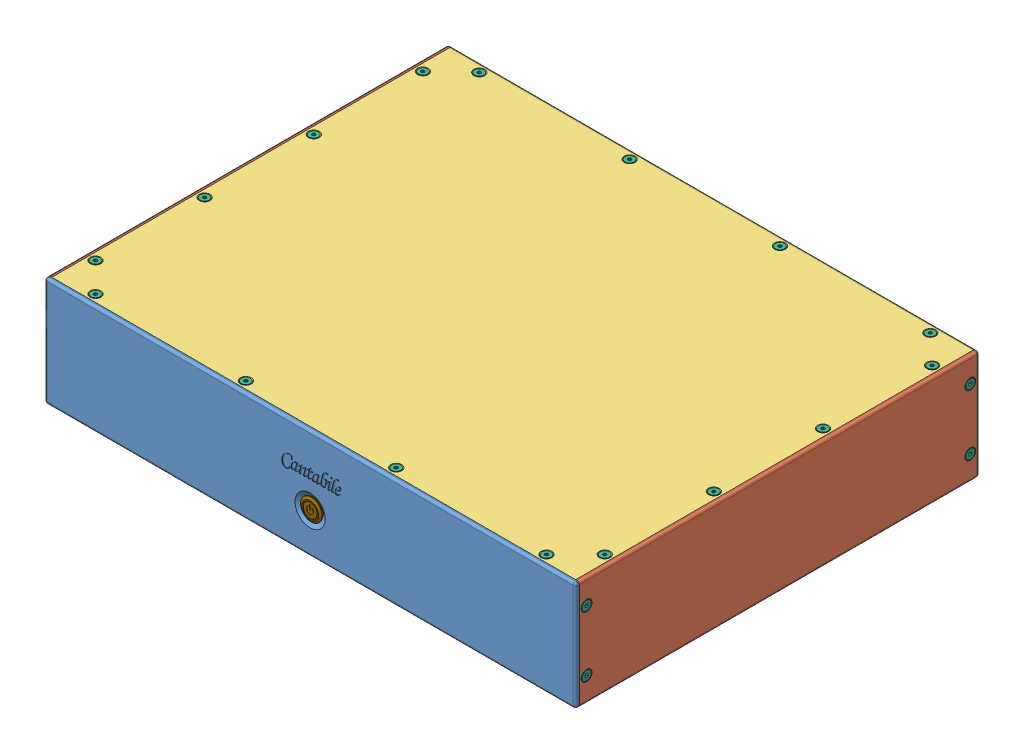
SolidWorks assembly 組合, configuration 預設. Lengths in mm.
Overall size (438 90 338.01).
55 component instances, 9 part files, 72 mates.
Components (placement in the parent):
- FrontPanel-1: FrontPanel [預設] at (-0.5858 -0.5858 -10.5) size (438 90 12.5)
- SidePanel-1: SidePanel [預設] at (437.4142 89.4142 -1) x (0 0 -1) z (-1 0 0) size (330 90 12.5)
- SidePanel-2: SidePanel [預設] at (-0.5858 -0.5858 -1) x (0 0 -1) z (1 0 0) size (330 90 12.5)
- TOP-1: TOP [預設] at (434.4142 85.4142 -331) x (-1 0 0) z (0 0 -1) size (432 4 330)
- Bottom-1: Bottom [預設] at (2.4142 3.4142 -331) x (1 0 0) z (0 0 -1) size (432 4 330)
- BackPanel-1: BackPanel [預設] at (424.9142 3.4142 -318.5) x (-1 0 0) z (0 0 -1) size (413 82 12.5)
- socket countersunk head screw_iso-1: socket countersunk head screw_iso [ISO 10642 - M4 x 8 --- 8N] at (404.4142 89.4142 -7) x (0 -1 0) z (0 0 1) size (8 7.53 7.53)
- socket countersunk head screw_iso-2: socket countersunk head screw_iso [ISO 10642 - M4 x 8 --- 8N] at (437.4142 69.4142 -323.5) x (-1 0 0) z (0 0.924225 0.381849) size (8 7.53 7.53)
- socket countersunk head screw_iso-3: socket countersunk head screw_iso [ISO 10642 - M4 x 8 --- 8N] at (280.4142 89.4142 -323.5) x (0 -1 0) z (0 0 1) size (8 7.53 7.53)
- socket countersunk head screw_iso-4: socket countersunk head screw_iso [ISO 10642 - M4 x 8 --- 8N] at (428.4142 89.4142 -211) x (0 -1 0) z (0 0 1) size (8 7.53 7.53)
- socket countersunk head screw_iso-5: socket countersunk head screw_iso [ISO 10642 - M4 x 8 --- 8N] at (404.4142 89.4142 -323.5) x (0 -1 0) z (0 0 1) size (8 7.53 7.53)
- socket countersunk head screw_iso-6: socket countersunk head screw_iso [ISO 10642 - M4 x 8 --- 8N] at (437.4142 19.4142 -323.5) x (-1 0 0) z (0 0.924225 0.381849) size (8 7.53 7.53)
- socket countersunk head screw_iso-7: socket countersunk head screw_iso [ISO 10642 - M4 x 8 --- 8N] at (428.4142 89.4142 -301) x (0 -1 0) z (0 0 1) size (8 7.53 7.53)
- socket countersunk head screw_iso-8: socket countersunk head screw_iso [ISO 10642 - M4 x 8 --- 8N] at (428.4142 89.4142 -121) x (0 -1 0) z (0 0 1) size (8 7.53 7.53)
- socket countersunk head screw_iso-9: socket countersunk head screw_iso [ISO 10642 - M4 x 8 --- 8N] at (428.4142 89.4142 -31) x (0 -1 0) z (0 0 1) size (8 7.53 7.53)
- socket countersunk head screw_iso-10: socket countersunk head screw_iso [ISO 10642 - M4 x 8 --- 8N] at (8.4142 -0.5858 -31) x (0 1 0) z (0 0 1) size (8 7.53 7.53)
- socket countersunk head screw_iso-11: socket countersunk head screw_iso [ISO 10642 - M4 x 8 --- 8N] at (156.4142 89.4142 -7) x (0 -1 0) z (0 0 1) size (8 7.53 7.53)
- socket countersunk head screw_iso-12: socket countersunk head screw_iso [ISO 10642 - M4 x 8 --- 8N] at (8.4142 89.4142 -31) x (0 -1 0) z (0 0 1) size (8 7.53 7.53)
- socket countersunk head screw_iso-13: socket countersunk head screw_iso [ISO 10642 - M4 x 8 --- 8N] at (428.4142 -0.5858 -121) x (0 1 0) z (0 0 1) size (8 7.53 7.53)
- socket countersunk head screw_iso-14: socket countersunk head screw_iso [ISO 10642 - M4 x 8 --- 8N] at (32.4142 89.4142 -7) x (0 -1 0) z (0 0 1) size (8 7.53 7.53)
- socket countersunk head screw_iso-15: socket countersunk head screw_iso [ISO 10642 - M4 x 8 --- 8N] at (437.4142 69.4142 -7) x (-1 0 0) z (0 0.924225 0.381849) size (8 7.53 7.53)
- socket countersunk head screw_iso-16: socket countersunk head screw_iso [ISO 10642 - M4 x 8 --- 8N] at (437.4142 19.4142 -7) x (-1 0 0) z (0 0.924225 0.381849) size (8 7.53 7.53)
- socket countersunk head screw_iso-17: socket countersunk head screw_iso [ISO 10642 - M4 x 8 --- 8N] at (428.4142 -0.5858 -301) x (0 1 0) z (0 0 1) size (8 7.53 7.53)
- socket countersunk head screw_iso-18: socket countersunk head screw_iso [ISO 10642 - M4 x 8 --- 8N] at (280.4142 89.4142 -7) x (0 -1 0) z (0 0 1) size (8 7.53 7.53)
- socket countersunk head screw_iso-19: socket countersunk head screw_iso [ISO 10642 - M4 x 8 --- 8N] at (8.4142 89.4142 -121) x (0 -1 0) z (0 0 1) size (8 7.53 7.53)
- socket countersunk head screw_iso-20: socket countersunk head screw_iso [ISO 10642 - M4 x 8 --- 8N] at (280.4142 -0.5858 -323.5) x (0 1 0) z (0 0 1) size (8 7.53 7.53)
- socket countersunk head screw_iso-21: socket countersunk head screw_iso [ISO 10642 - M4 x 8 --- 8N] at (156.4142 -0.5858 -323.5) x (0 1 0) z (0 0 1) size (8 7.53 7.53)
- socket countersunk head screw_iso-22: socket countersunk head screw_iso [ISO 10642 - M4 x 8 --- 8N] at (428.4142 -0.5858 -211) x (0 1 0) z (0 0 1) size (8 7.53 7.53)
- socket countersunk head screw_iso-23: socket countersunk head screw_iso [ISO 10642 - M4 x 8 --- 8N] at (428.4142 -0.5858 -31) x (0 1 0) z (0 0 1) size (8 7.53 7.53)
- socket countersunk head screw_iso-24: socket countersunk head screw_iso [ISO 10642 - M4 x 8 --- 8N] at (32.4142 -0.5858 -323.5) x (0 1 0) z (0 0 1) size (8 7.53 7.53)
- socket countersunk head screw_iso-25: socket countersunk head screw_iso [ISO 10642 - M4 x 8 --- 8N] at (156.4142 89.4142 -323.5) x (0 -1 0) z (0 0 1) size (8 7.53 7.53)
- socket countersunk head screw_iso-26: socket countersunk head screw_iso [ISO 10642 - M4 x 8 --- 8N] at (404.4142 -0.5858 -7) x (0 1 0) z (0 0 1) size (8 7.53 7.53)
- socket countersunk head screw_iso-27: socket countersunk head screw_iso [ISO 10642 - M4 x 8 --- 8N] at (8.4142 89.4142 -301) x (0 -1 0) z (0 0 1) size (8 7.53 7.53)
- socket countersunk head screw_iso-28: socket countersunk head screw_iso [ISO 10642 - M4 x 8 --- 8N] at (280.4142 -0.5858 -7) x (0 1 0) z (0 0 1) size (8 7.53 7.53)
- socket countersunk head screw_iso-29: socket countersunk head screw_iso [ISO 10642 - M4 x 8 --- 8N] at (32.4142 89.4142 -323.5) x (0 -1 0) z (0 0 1) size (8 7.53 7.53)
- socket countersunk head screw_iso-30: socket countersunk head screw_iso [ISO 10642 - M4 x 8 --- 8N] at (8.4142 -0.5858 -211) x (0 1 0) z (0 0 1) size (8 7.53 7.53)
- socket countersunk head screw_iso-31: socket countersunk head screw_iso [ISO 10642 - M4 x 8 --- 8N] at (8.4142 89.4142 -211) x (0 -1 0) z (0 0 1) size (8 7.53 7.53)
- socket countersunk head screw_iso-32: socket countersunk head screw_iso [ISO 10642 - M4 x 8 --- 8N] at (156.4142 -0.5858 -7) x (0 1 0) z (0 0 1) size (8 7.53 7.53)
- socket countersunk head screw_iso-33: socket countersunk head screw_iso [ISO 10642 - M4 x 8 --- 8N] at (32.4142 -0.5858 -7) x (0 1 0) z (0 0 1) size (8 7.53 7.53)
- socket countersunk head screw_iso-34: socket countersunk head screw_iso [ISO 10642 - M4 x 8 --- 8N] at (8.4142 -0.5858 -301) x (0 1 0) z (0 0 1) size (8 7.53 7.53)
- socket countersunk head screw_iso-35: socket countersunk head screw_iso [ISO 10642 - M4 x 8 --- 8N] at (8.4142 -0.5858 -121) x (0 1 0) z (0 0 1) size (8 7.53 7.53)
- socket countersunk head screw_iso-36: socket countersunk head screw_iso [ISO 10642 - M4 x 8 --- 8N] at (-0.5858 19.4142 -323.5) size (8 7.53 7.53)
- socket countersunk head screw_iso-37: socket countersunk head screw_iso [ISO 10642 - M4 x 8 --- 8N] at (-0.5858 19.4142 -7) size (8 7.53 7.53)
- socket countersunk head screw_iso-38: socket countersunk head screw_iso [ISO 10642 - M4 x 8 --- 8N] at (-0.5858 69.4142 -7) x (1 0 0) z (0 0 -1) size (8 7.53 7.53)
- socket countersunk head screw_iso-39: socket countersunk head screw_iso [ISO 10642 - M4 x 8 --- 8N] at (-0.5858 69.4142 -323.5) size (8 7.53 7.53)
- RCA-1: RCA [預設] at (61.9142 44.4142 -329) x (1 0 0) z (0 0 -1) size (26 31 28.3)
- RCA-2: RCA [預設] at (374.9142 44.4142 -329) x (1 0 0) z (0 0 -1) size (26 31 28.3)
- socket countersunk head screw_iso-40: socket countersunk head screw_iso [ISO 10642 - M3 x 8 --- 8N] at (365.4142 32.4142 -331.36) x (0 0 1) z (-1 0 0) size (8 5.54 5.54)
- socket countersunk head screw_iso-41: socket countersunk head screw_iso [ISO 10642 - M3 x 8 --- 8N] at (384.4142 56.4142 -331.36) x (0 0 1) z (-1 0 0) size (8 5.54 5.54)
- socket countersunk head screw_iso-42: socket countersunk head screw_iso [ISO 10642 - M3 x 8 --- 8N] at (71.4142 56.4142 -331.36) x (0 0 1) z (-1 0 0) size (8 5.54 5.54)
- socket countersunk head screw_iso-43: socket countersunk head screw_iso [ISO 10642 - M3 x 8 --- 8N] at (200.4142 28.6642 -333.0929) x (0 0 1) z (-1 0 0) size (8 5.54 5.54)
- socket countersunk head screw_iso-44: socket countersunk head screw_iso [ISO 10642 - M3 x 8 --- 8N] at (52.4142 32.4142 -331.36) x (0 0 1) z (-1 0 0) size (8 5.54 5.54)
- socket countersunk head screw_iso-45: socket countersunk head screw_iso [ISO 10642 - M3 x 8 --- 8N] at (236.4142 28.6642 -333.0929) x (0 0 1) z (-1 0 0) size (8 5.54 5.54)
- IEC-320-1: IEC-320 [預設] at (218.4142 22.9642 -333.5) x (-1 0 0) z (0 0 -1) size (44.12 34 28.26)
- LED SWITCH-1: LED SWITCH [預設] at (218.4142 32.4142 0.5) size (17.8 17.8 37.5)
Mates (geometry in assembly coordinates):
- 重合/共線/共點3: coincident anti-aligned: plane of FrontPanel-1 through (437.4142 -0.5858 -1) normal (0 0 -1); plane of SidePanel-2 through (11.9142 -0.5858 -1) normal (0 0 1)
- 重合/共線/共點4: coincident anti-aligned: line of FrontPanel-1 through (11.9142 85.4142 -1) axis (0 0 -1); line of SidePanel-2 through (11.9142 85.4142 -331) axis (0 0 1)
- 重合/共線/共點8: coordinate: moEndPointRef_w of FrontPanel-1; point of assembly
- 重合/共線/共點16: coincident anti-aligned: plane of FrontPanel-1 through (437.4142 -0.5858 -1) normal (0 0 -1); plane of SidePanel-1 through (424.9142 89.4142 -1) normal (0 0 1)
- 重合/共線/共點17: coincident anti-aligned: line of FrontPanel-1 through (424.9142 3.4142 -1) axis (0 0 -1); line of SidePanel-1 through (424.9142 3.4142 -331) axis (0 0 1)
- 重合/共線/共點53: coincident anti-aligned: plane of FrontPanel-1 through (11.9142 -0.5858 -10.5) normal (-1 0 0); plane of SidePanel-2 through (11.9142 -0.5858 -1) normal (1 0 0)
- 重合/共線/共點56: coincident anti-aligned: plane of SidePanel-2 through (11.9142 85.4142 -331) normal (0 1 0); plane of TOP-1 through (434.4142 85.4142 -331) normal (0 -1 0)
- 重合/共線/共點57: coincident aligned: line of FrontPanel-1 through (11.9142 85.4142 -1) axis (1 0 0); line of TOP-1 through (2.4142 85.4142 -1) axis (1 0 0)
- 重合/共線/共點58: coincident anti-aligned: line of SidePanel-1 through (434.4142 89.4142 -329) axis (0 0 1); line of TOP-1 through (434.4142 89.4142 -1) axis (0 0 -1)
- 重合/共線/共點75: coincident anti-aligned: plane of SidePanel-1 through (434.4142 -0.5858 -331) normal (-1 0 0); plane of Bottom-1 through (434.4142 -0.5858 -331) normal (1 0 0)
- 重合/共線/共點76: coincident anti-aligned: line of SidePanel-1 through (434.4142 3.4142 -331) axis (-1 0 0); line of Bottom-1 through (2.4142 3.4142 -331) axis (1 0 0)
- 重合/共線/共點77: coincident anti-aligned: plane of SidePanel-2 through (11.9142 3.4142 -331) normal (0 -1 0); plane of Bottom-1 through (2.4142 3.4142 -331) normal (0 1 0)
- 重合/共線/共點78: coincident aligned: cone of SidePanel-1 through (437.4142 69.4142 -323.5) axis (-1 0 0); cone of socket countersunk head screw_iso-2 through (436.6992 69.4142 -323.5) axis (-1 0 0)
- 重合/共線/共點79: coincident aligned: cone of SidePanel-1 through (437.4142 19.4142 -323.5) axis (-1 0 0); cone of socket countersunk head screw_iso-6 through (436.6992 19.4142 -323.5) axis (-1 0 0)
- 重合/共線/共點80: coincident aligned: cone of TOP-1 through (404.4142 89.4142 -323.5) axis (0 -1 0); cone of socket countersunk head screw_iso-5 through (404.4142 88.6992 -323.5) axis (0 -1 0)
- 重合/共線/共點81: coincident aligned: cone of TOP-1 through (280.4142 89.4142 -323.5) axis (0 -1 0); cone of socket countersunk head screw_iso-3 through (280.4142 88.6992 -323.5) axis (0 -1 0)
- 重合/共線/共點82: coincident aligned: cone of TOP-1 through (428.4142 89.4142 -211) axis (0 -1 0); cone of socket countersunk head screw_iso-4 through (428.4142 88.6992 -211) axis (0 -1 0)
- 重合/共線/共點83: coincident aligned: cone of TOP-1 through (428.4142 89.4142 -301) axis (0 -1 0); cone of socket countersunk head screw_iso-7 through (428.4142 88.6992 -301) axis (0 -1 0)
- 重合/共線/共點84: coincident aligned: cone of TOP-1 through (428.4142 89.4142 -121) axis (0 -1 0); cone of socket countersunk head screw_iso-8 through (428.4142 88.6992 -121) axis (0 -1 0)
- 重合/共線/共點85: coincident aligned: cone of TOP-1 through (156.4142 89.4142 -323.5) axis (0 -1 0); cone of socket countersunk head screw_iso-25 through (156.4142 88.6992 -323.5) axis (0 -1 0)
- 重合/共線/共點86: coincident aligned: cone of TOP-1 through (428.4142 89.4142 -31) axis (0 -1 0); cone of socket countersunk head screw_iso-9 through (428.4142 88.6992 -31) axis (0 -1 0)
- 重合/共線/共點87: coincident aligned: cone of TOP-1 through (404.4142 89.4142 -7) axis (0 -1 0); cone of socket countersunk head screw_iso-1 through (404.4142 88.6992 -7) axis (0 -1 0)
- 重合/共線/共點88: coincident aligned: cone of SidePanel-1 through (437.4142 69.4142 -7) axis (-1 0 0); cone of socket countersunk head screw_iso-15 through (436.6992 69.4142 -7) axis (-1 0 0)
- 重合/共線/共點89: coincident aligned: cone of SidePanel-1 through (437.4142 19.4142 -7) axis (-1 0 0); cone of socket countersunk head screw_iso-16 through (436.6992 19.4142 -7) axis (-1 0 0)
- 重合/共線/共點90: coincident aligned: cone of TOP-1 through (280.4142 89.4142 -7) axis (0 -1 0); cone of socket countersunk head screw_iso-18 through (280.4142 88.6992 -7) axis (0 -1 0)
- 重合/共線/共點91: coincident aligned: cone of TOP-1 through (32.4142 89.4142 -323.5) axis (0 -1 0); cone of socket countersunk head screw_iso-29 through (32.4142 88.6992 -323.5) axis (0 -1 0)
- 重合/共線/共點92: coincident aligned: cone of TOP-1 through (8.4142 89.4142 -301) axis (0 -1 0); cone of socket countersunk head screw_iso-27 through (8.4142 88.6992 -301) axis (0 -1 0)
- 重合/共線/共點93: coincident aligned: cone of TOP-1 through (8.4142 89.4142 -211) axis (0 -1 0); cone of socket countersunk head screw_iso-31 through (8.4142 88.6992 -211) axis (0 -1 0)
- 重合/共線/共點94: coincident aligned: cone of TOP-1 through (8.4142 89.4142 -121) axis (0 -1 0); cone of socket countersunk head screw_iso-19 through (8.4142 88.6992 -121) axis (0 -1 0)
- 重合/共線/共點95: coincident aligned: cone of TOP-1 through (156.4142 89.4142 -7) axis (0 -1 0); cone of socket countersunk head screw_iso-11 through (156.4142 88.6992 -7) axis (0 -1 0)
- 重合/共線/共點96: coincident: circle of TOP-1; cone of socket countersunk head screw_iso-12 through (8.4142 88.6992 -31) axis (0 -1 0)
- 重合/共線/共點97: coincident aligned: cone of TOP-1 through (32.4142 89.4142 -7) axis (0 -1 0); cone of socket countersunk head screw_iso-14 through (32.4142 88.6992 -7) axis (0 -1 0)
- 重合/共線/共點98: coincident aligned: cone of Bottom-1 through (428.4142 -0.5858 -301) axis (0 1 0); cone of socket countersunk head screw_iso-17 through (428.4142 0.1292 -301) axis (0 1 0)
- 重合/共線/共點99: coincident aligned: cone of Bottom-1 through (280.4142 -0.5858 -323.5) axis (0 1 0); cone of socket countersunk head screw_iso-20 through (280.4142 0.1292 -323.5) axis (0 1 0)
- 重合/共線/共點100: coincident: cone of Bottom-1 through (156.4142 -0.5858 -323.5) axis (0 1 0); circle of socket countersunk head screw_iso-21
- 重合/共線/共點101: coincident aligned: cone of Bottom-1 through (32.4142 -0.5858 -323.5) axis (0 1 0); cone of socket countersunk head screw_iso-24 through (32.4142 0.1292 -323.5) axis (0 1 0)
- 重合/共線/共點102: coincident aligned: cone of Bottom-1 through (428.4142 -0.5858 -211) axis (0 1 0); cone of socket countersunk head screw_iso-22 through (428.4142 0.1292 -211) axis (0 1 0)
- 重合/共線/共點103: coincident aligned: cone of Bottom-1 through (428.4142 -0.5858 -121) axis (0 1 0); cone of socket countersunk head screw_iso-13 through (428.4142 0.1292 -121) axis (0 1 0)
- 重合/共線/共點105: coincident aligned: cone of Bottom-1 through (428.4142 -0.5858 -31) axis (0 1 0); cone of socket countersunk head screw_iso-23 through (428.4142 0.1292 -31) axis (0 1 0)
- 重合/共線/共點106: coincident aligned: cone of Bottom-1 through (404.4142 -0.5858 -7) axis (0 1 0); cone of socket countersunk head screw_iso-26 through (404.4142 0.1292 -7) axis (0 1 0)
- 重合/共線/共點107: coincident aligned: cone of Bottom-1 through (280.4142 -0.5858 -7) axis (0 1 0); cone of socket countersunk head screw_iso-28 through (280.4142 0.1292 -7) axis (0 1 0)
- 重合/共線/共點108: coincident aligned: cone of Bottom-1 through (156.4142 -0.5858 -7) axis (0 1 0); cone of socket countersunk head screw_iso-32 through (156.4142 0.1292 -7) axis (0 1 0)
- 重合/共線/共點109: coincident aligned: cone of Bottom-1 through (32.4142 -0.5858 -7) axis (0 1 0); cone of socket countersunk head screw_iso-33 through (32.4142 0.1292 -7) axis (0 1 0)
- 重合/共線/共點110: coincident aligned: cone of Bottom-1 through (8.4142 -0.5858 -301) axis (0 1 0); cone of socket countersunk head screw_iso-34 through (8.4142 0.1292 -301) axis (0 1 0)
- 重合/共線/共點111: coincident aligned: cone of Bottom-1 through (8.4142 -0.5858 -211) axis (0 1 0); cone of socket countersunk head screw_iso-30 through (8.4142 0.1292 -211) axis (0 1 0)
- 重合/共線/共點112: coincident aligned: cone of Bottom-1 through (8.4142 -0.5858 -121) axis (0 1 0); cone of socket countersunk head screw_iso-35 through (8.4142 0.1292 -121) axis (0 1 0)
- 重合/共線/共點113: coincident aligned: cone of Bottom-1 through (8.4142 -0.5858 -31) axis (0 1 0); cone of socket countersunk head screw_iso-10 through (8.4142 0.1292 -31) axis (0 1 0)
- 重合/共線/共點115: coincident aligned: cone of SidePanel-2 through (-0.5858 19.4142 -323.5) axis (1 0 0); cone of socket countersunk head screw_iso-36 through (0.1292 19.4142 -323.5) axis (1 0 0)
- 重合/共線/共點116: coincident aligned: cone of SidePanel-2 through (-0.5858 19.4142 -7) axis (1 0 0); cone of socket countersunk head screw_iso-37 through (0.1292 19.4142 -7) axis (1 0 0)
- 重合/共線/共點117: coincident aligned: cone of SidePanel-2 through (-0.5858 69.4142 -323.5) axis (1 0 0); cone of socket countersunk head screw_iso-39 through (0.1292 69.4142 -323.5) axis (1 0 0)
- 重合/共線/共點118: coincident aligned: cone of SidePanel-2 through (-0.5858 69.4142 -7) axis (1 0 0); cone of socket countersunk head screw_iso-38 through (0.1292 69.4142 -7) axis (1 0 0)
- 重合/共線/共點123: coincident anti-aligned: plane of SidePanel-2 through (11.9142 -0.5858 -1) normal (1 0 0); plane of BackPanel-1 through (11.9142 3.4142 -331) normal (-1 0 0)
- 重合/共線/共點125: coincident anti-aligned: line of Bottom-1 through (2.4142 3.4142 -331) axis (1 0 0); line of BackPanel-1 through (424.9142 3.4142 -331) axis (-1 0 0)
- 重合/共線/共點126: coincident anti-aligned: line of TOP-1 through (434.4142 85.4142 -331) axis (-1 0 0); line of BackPanel-1 through (11.9142 85.4142 -331) axis (1 0 0)
- 重合/共線/共點130: coincident: cone of RCA-2 through (365.4142 32.4142 -391.7387) axis (0 0 1); circle of socket countersunk head screw_iso-40
- 重合/共線/共點131: coincident: circle of RCA-2; cone of socket countersunk head screw_iso-41 through (384.4142 56.4142 -391.5087) axis (0 0 1)
- 重合/共線/共點132: coincident: circle of RCA-1; cone of socket countersunk head screw_iso-44 through (52.4142 32.4142 -330.77) axis (0 0 1)
- 重合/共線/共點133: coincident: circle of RCA-1; cone of socket countersunk head screw_iso-42 through (71.4142 56.4142 -330.77) axis (0 0 1)
- 重合/共線/共點134: coincident anti-aligned: plane of BackPanel-1 through (424.9142 3.4142 -331) normal (0 0 -1); plane of IEC-320-1 through (196.1502 11.6642 -331) normal (0 0 1)
- 同軸心9: concentric aligned: circle of BackPanel-1; circle of IEC-320-1
- 同軸心10: concentric aligned: cone of BackPanel-1 through (236.4142 28.6642 -331) axis (0 0 1); cone of IEC-320-1 through (236.4142 28.6642 -331.6) axis (0 0 1)
- 重合/共線/共點135: coincident: cone of socket countersunk head screw_iso-45 through (236.4142 28.6642 -332.5029) axis (0 0 1); circle of IEC-320-1
- 重合/共線/共點136: coincident: cone of socket countersunk head screw_iso-43 through (200.4142 28.6642 -332.5029) axis (0 0 1); circle of IEC-320-1
- 同軸心12: concentric anti-aligned: circle of FrontPanel-1; circle of LED SWITCH-1
- 重合/共線/共點137: coincident aligned: plane of FrontPanel-1 through (-0.5858 -0.5858 2) normal (0 0 1); plane of LED SWITCH-1 through (212.747 26.747 2) normal (0 0 1)
- 垂直1: perpendicular: line of FrontPanel-1 through (435.4142 87.4142 2) axis (-1 0 0); line of LED SWITCH-1 through (218.6642 32.5642 1.85) axis (0 1 0)
- 同軸心13: concentric aligned: cylinder of BackPanel-1 through (365.4142 32.4142 -331) axis (0 0 -1) radius 1.25; circle of RCA-2
- 同軸心15: concentric aligned: circle of BackPanel-1; circle of RCA-2
- 同軸心16: concentric aligned: circle of BackPanel-1; circle of RCA-1
- 同軸心17: concentric aligned: circle of BackPanel-1; circle of RCA-1
- 重合/共線/共點143: coincident anti-aligned: plane of BackPanel-1 through (424.9142 3.4142 -329) normal (0 0 -1); plane of RCA-1 through (61.9142 44.4142 -329) normal (0 0 1)
- 重合/共線/共點144: coincident anti-aligned: plane of BackPanel-1 through (424.9142 3.4142 -329) normal (0 0 -1); plane of RCA-2 through (374.9142 44.4142 -329) normal (0 0 1)
